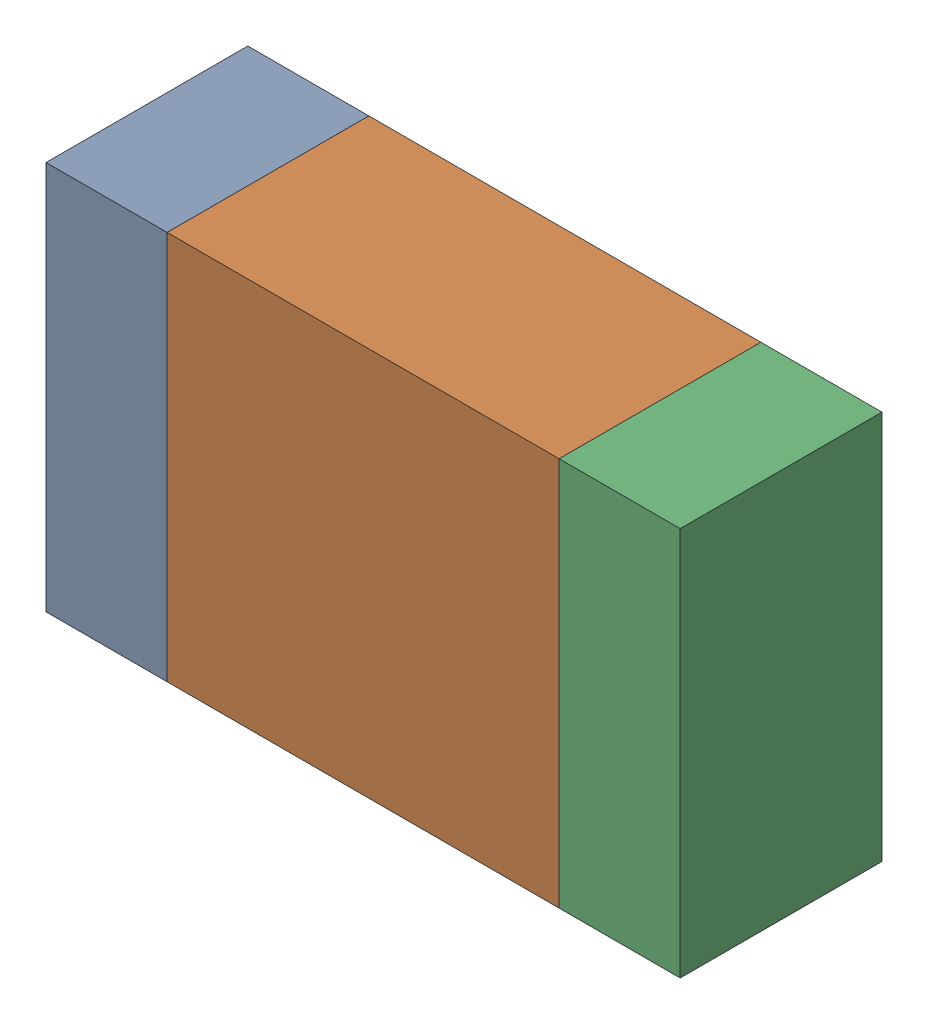
SolidWorks assembly R13, configuration Default. Lengths in mm.
Overall size (2.2 1.35 0.7).
6 component instances, 2 part files, 0 mates.
Components (placement in the parent):
- 959209344-1: 959209344 [Default] at (105.4089 93.8529 0) size (0.42 1.35 0.7)
  - Extruded-25-1: Extruded-25 [Default] at origin size (0.42 1.35 0.7)
- 959209480-1: 959209480 [Default] at (106.2989 93.8529 0) size (1.36 1.35 0.7)
  - Extruded-26-1: Extruded-26 [Default] at origin size (1.36 1.35 0.7)
- 959209344-2: 959209344 [Default] at (107.1889 93.8529 0) size (0.42 1.35 0.7)
  - Extruded-25-1: Extruded-25 [Default] at origin size (0.42 1.35 0.7)
